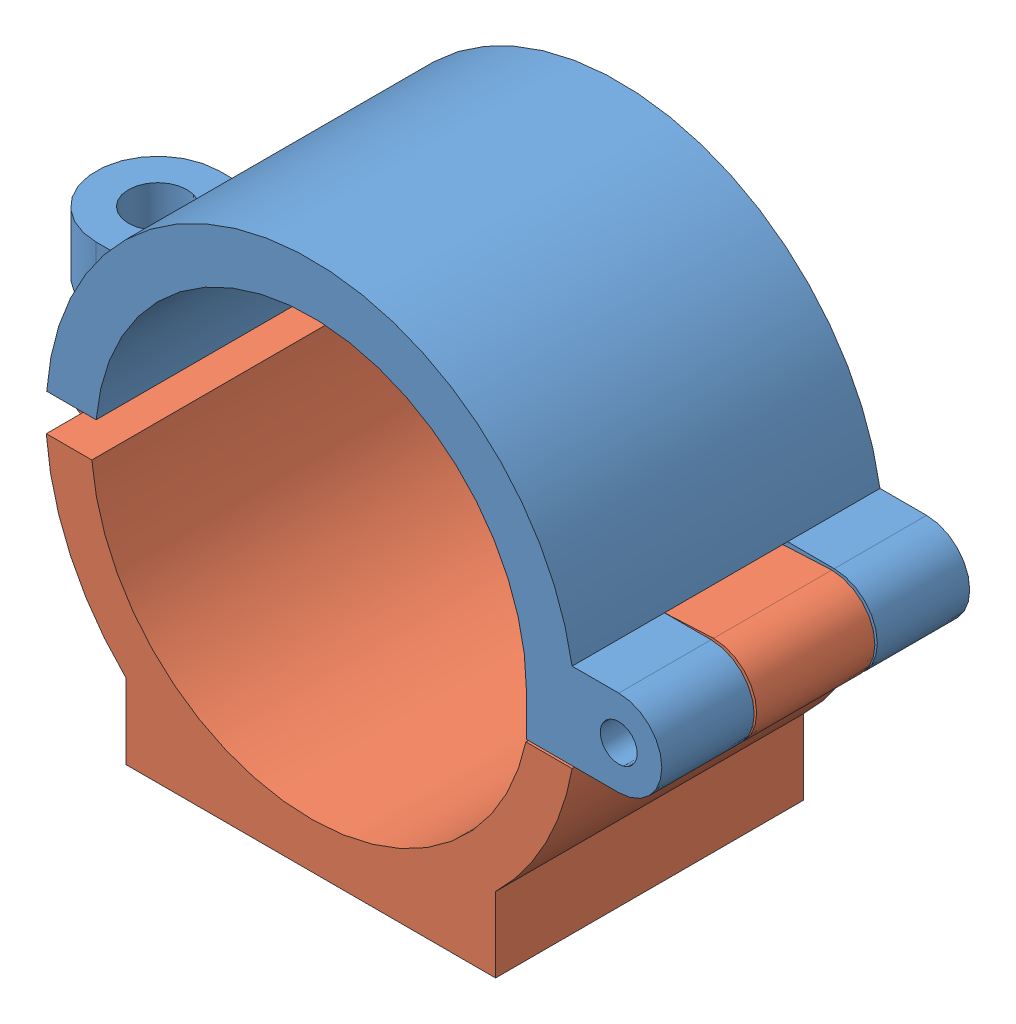
SolidWorks assembly Assemblage1, configuration Défaut. Lengths in mm.
Overall size (58.44 43.04 25).
2 component instances, 2 part files, 4 mates.
Components (placement in the parent):
- piece1-1: piece1 [Défaut] at (-59.898 -5.1693 -12.5) size (58.44 25 25)
- Pièce2-1: Pièce2 [Défaut] at (-59.898 -3.6693 -12.5) x (-1 0 0) z (0 -1 0) size (58.44 25 25.04)
Mates (geometry in assembly coordinates):
- Sur place1: in place: plane of piece1-1 through (-77.1389 -2.1693 12.5) normal (0 -1 0); plane of ? through (0 -2.1693 0) normal (0 -1 0); moOrthogonalPlaneRef_w of piece1-1 through (-77.1389 -2.1693 12.5) normal (0 -1 0); unknown of ?; plane of piece1-1 through (-77.1389 -2.1693 12.5) normal (0 -1 0); line of ? through (-55 0 -2.1693) axis (0 -1 0); plane of piece1-1 through (-77.3336 -3.6693 12.5) normal (0 -1 0); unknown of Pièce2-1
- Coïncidente1: coincident aligned: plane of piece1-1; plane of Pièce2-1
- Coïncidente2: coincident aligned: moOrthogonalPlaneRef_w of piece1-1 through (-59.898 -3.6693 -12.5) normal (0 0 -1); plane of Pièce2-1
- Coïncidente3: coincident anti-aligned: moOrthogonalPlaneRef_w of piece1-1 through (-59.898 -3.6693 -12.5) normal (1 0 0); plane of Pièce2-1
